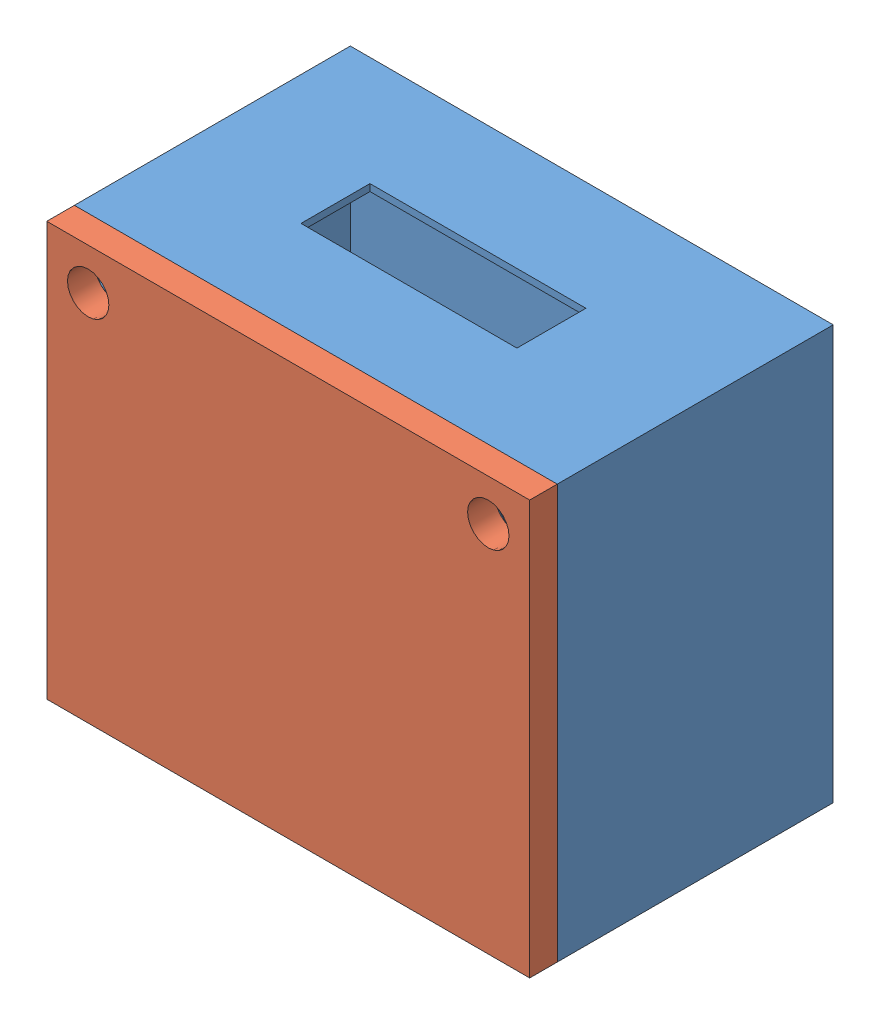
SolidWorks assembly Assem3, configuration Default. Lengths in mm.
Overall size (35 30 22).
2 component instances, 2 part files, 1 mates.
Components (placement in the parent):
- imu1-1: imu1 [Default] at (4.7512 11.3642 35.9406) size (35 30 20)
- imu2-1: imu2 [Default] at (17.9509 33.3011 55.9406) size (35 30 2)
Mates (geometry in assembly coordinates):
- Coincident2: coincident: point of imu1-1; point of imu2-1
